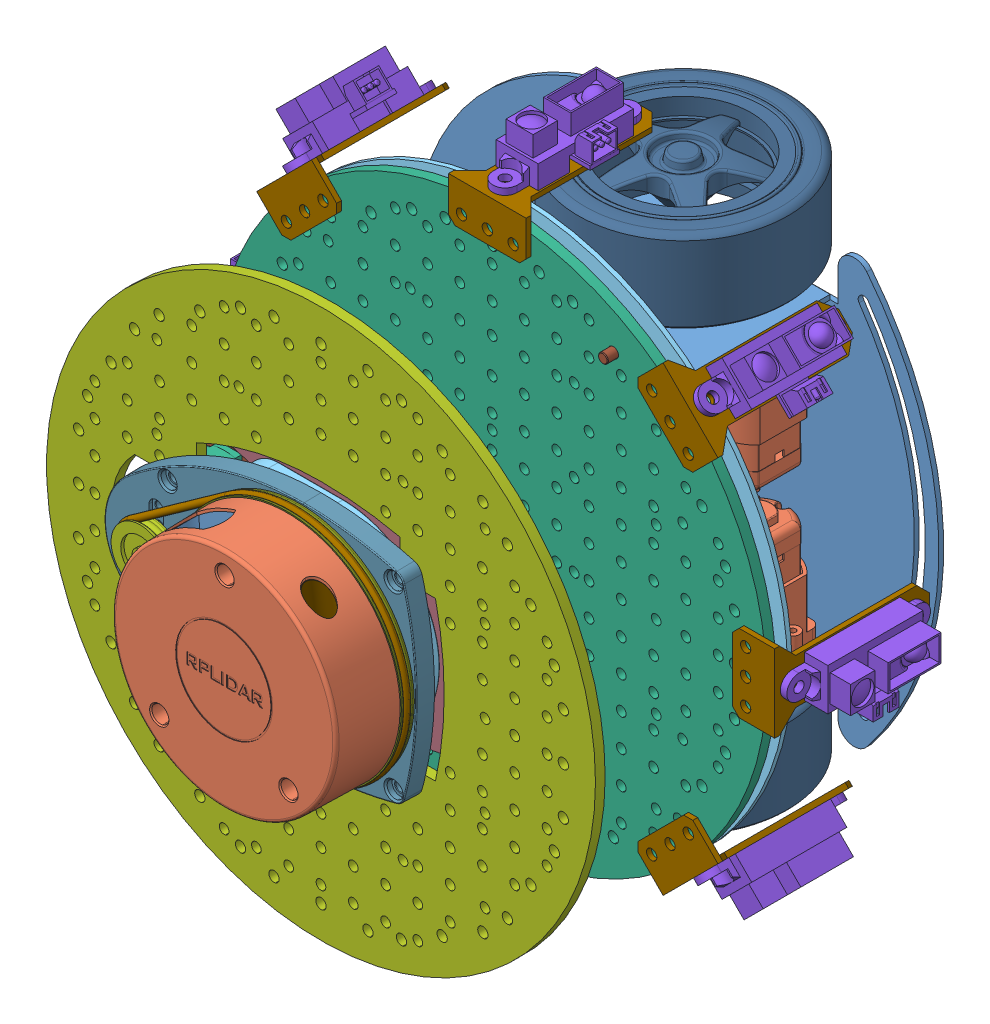
SolidWorks assembly ABOT_2, configuration По умолчанию. Lengths in mm.
Overall size (205 205 173.81).
51 component instances, 33 part files, 41 mates.
Components (placement in the parent):
- LOWER_PLATE-1: LOWER_PLATE [По умолчанию] x (0 1 0) z (1 0 0) size (144.85 55.5 162.2)
- TT_ANGLE_MOTOR_PART-1: TT_ANGLE_MOTOR_PART [По умолчанию] at (11.0834 -43.5 12.4406) x (-1 0 0) z (0 1 0) size (47.1 23 58.3)
- TT_ANGLE_MOTOR_PART-2: TT_ANGLE_MOTOR_PART [По умолчанию] at (11.0834 43.5 16.5594) x (-1 0 0) z (0 -1 0) size (47.1 23 58.3)
- CASTER_WHEEL_CASE-1: CASTER_WHEEL_CASE [Default] at (-78 0 -11) x (0 1 0) z (1 0 0) size (48.4 16.5 32.2)
- CASTER_WHEEL_BALL-1: CASTER_WHEEL_BALL [Default] at (-78 0 -11) x (0 1 0) z (1 0 0) size (14 14 14)
- UPPER_PLATE-1: UPPER_PLATE [Default] at (-10 0 55.5) x (-1 0 0) z (0 0 1) size (169.5 169.5 1.4)
- CUT_PLEX_PLATE_0-1: CUT_PLEX_PLATE_0 [Default] at (-10 0 60.65) x (-1 0 0) z (0 0 1) size (170 170 3)
- CUT_PLEX_PLATE_1-1: CUT_PLEX_PLATE_1 [По умолчанию] at (-10 0 113.65) x (-1 0 0) z (0 0 1) size (170 170 3)
- GP2Y0A41SK0F_AXIS_FRAME-1: GP2Y0A41SK0F_AXIS_FRAME [По умолчанию] at (92.5 0 41.15) x (0 0 -1) z (0 -1 0) size (44.5 13.5 18.9)
- PRINT_SHARP_IR_MOUNTING_BRACKET_VERTICAL-1: PRINT_SHARP_IR_MOUNTING_BRACKET_VERTICAL [Default] at (79 0 65.15) x (-1 0 0) z (0 -1 0) size (13 48 24)
- WHEEL_D65_W26-1: WHEEL_D65_W26 [Predeterminado] at (0 68 14.5) x (0 1 0) z (-0.04348 0 0.999054) size (29 65 65)
- WHEEL_D65_W26-2: WHEEL_D65_W26 [Predeterminado] at (0 -68 14.5) x (0 -1 0) z (-0.342045 0 0.939684) size (29 65 65)
- M3_12H-1: M3_12H [По умолчанию] at (27.525 64.9952 52.9) x (0 0 1) z (-1 0 0) size (14 5.5 5.5)
- M3_NUT-1: M3_NUT [По умолчанию] at (27.525 64.9952 57.5) x (0.986628 0.162989 0) z (0 0 1) size (5.5 6.35 2.4)
- M3_WASHER_NORMAL-1: M3_WASHER_NORMAL [Default] at (27.525 64.9952 55.5) x (-1 0 0) z (0 0 -1) size (6.75 6.75 0.6)
- M3_WASHER_NORMAL-2: M3_WASHER_NORMAL [Default] at (27.525 64.9952 56.9) x (0.997695 0.06786 0) z (0 0 1) size (6.75 6.75 0.6)
- GP2Y0A41SK0F_AXIS_FRAME-13: GP2Y0A41SK0F_AXIS_FRAME [По умолчанию] at (62.4784 -72.4784 41.15) x (0 0 -1) z (-0.707107 -0.707107 0) size (44.5 13.5 18.9)
- GP2Y0A41SK0F_AXIS_FRAME-14: GP2Y0A41SK0F_AXIS_FRAME [По умолчанию] at (-10 -102.5 41.15) x (0 0 -1) z (-1 0 0) size (44.5 13.5 18.9)
- GP2Y0A41SK0F_AXIS_FRAME-15: GP2Y0A41SK0F_AXIS_FRAME [По умолчанию] at (-82.4784 -72.4784 41.15) x (0 0 -1) z (-0.707107 0.707107 0) size (44.5 13.5 18.9)
- GP2Y0A41SK0F_AXIS_FRAME-16: GP2Y0A41SK0F_AXIS_FRAME [По умолчанию] at (-112.5 0 41.15) x (0 0 -1) z (0 1 0) size (44.5 13.5 18.9)
- GP2Y0A41SK0F_AXIS_FRAME-17: GP2Y0A41SK0F_AXIS_FRAME [По умолчанию] at (-82.4784 72.4784 41.15) x (0 0 -1) z (0.707107 0.707107 0) size (44.5 13.5 18.9)
- GP2Y0A41SK0F_AXIS_FRAME-18: GP2Y0A41SK0F_AXIS_FRAME [По умолчанию] at (-10 102.5 41.15) x (0 0 -1) z (1 0 0) size (44.5 13.5 18.9)
- GP2Y0A41SK0F_AXIS_FRAME-19: GP2Y0A41SK0F_AXIS_FRAME [По умолчанию] at (62.4784 72.4784 41.15) x (0 0 -1) z (0.707107 -0.707107 0) size (44.5 13.5 18.9)
- PRINT_SHARP_IR_MOUNTING_BRACKET_VERTICAL-9: PRINT_SHARP_IR_MOUNTING_BRACKET_VERTICAL [Default] at (52.9325 -62.9325 65.15) x (-0.707107 0.707107 0) z (-0.707107 -0.707107 0) size (13 48 24)
- PRINT_SHARP_IR_MOUNTING_BRACKET_VERTICAL-10: PRINT_SHARP_IR_MOUNTING_BRACKET_VERTICAL [Default] at (-10 -89 65.15) x (0 1 0) z (-1 0 0) size (13 48 24)
- PRINT_SHARP_IR_MOUNTING_BRACKET_VERTICAL-11: PRINT_SHARP_IR_MOUNTING_BRACKET_VERTICAL [Default] at (-72.9325 -62.9325 65.15) x (0.707107 0.707107 0) z (-0.707107 0.707107 0) size (13 48 24)
- PRINT_SHARP_IR_MOUNTING_BRACKET_VERTICAL-12: PRINT_SHARP_IR_MOUNTING_BRACKET_VERTICAL [Default] at (-99 0 65.15) x (1 0 0) z (0 1 0) size (13 48 24)
- PRINT_SHARP_IR_MOUNTING_BRACKET_VERTICAL-13: PRINT_SHARP_IR_MOUNTING_BRACKET_VERTICAL [Default] at (-72.9325 62.9325 65.15) x (0.707107 -0.707107 0) z (0.707107 0.707107 0) size (13 48 24)
- PRINT_SHARP_IR_MOUNTING_BRACKET_VERTICAL-14: PRINT_SHARP_IR_MOUNTING_BRACKET_VERTICAL [Default] at (-10 89 65.15) x (0 -1 0) z (1 0 0) size (13 48 24)
- PRINT_SHARP_IR_MOUNTING_BRACKET_VERTICAL-15: PRINT_SHARP_IR_MOUNTING_BRACKET_VERTICAL [Default] at (52.9325 62.9325 65.15) x (-0.707107 -0.707107 0) z (0.707107 -0.707107 0) size (13 48 24)
- LIDAR-1: LIDAR [По умолчанию] at (-79.4738 13.0661 98.954) x (-1 0 0) z (0 1 0) size (102.81 54.41 71.78)
  - 1-1: 1 [По умолчанию] at (-69.4738 21.696 -13.0661) size (96.74 12.71 70.28)
  - 2-1: 2 [По умолчанию] at (-69.4738 23.696 -13.0661) x (1 0 0) z (0 -1 0) size (47 47 7.01)
  - 3-1: 3 [По умолчанию] at (-69.4738 25.696 -13.0661) x (0.00451 0 -0.99999) z (0.99999 0 0.00451) size (70.79 21.41 70.79)
  - 4-1: 4 [По умолчанию] at (-94.6291 38.696 -19.9402) x (0.990886 0 -0.134705) z (0.134705 0 0.990886) size (6.5 6.5 21.2)
  - 5-1: 5 [По умолчанию] at (-69.4738 29.696 -13.0661) x (-0.99999 0 -0.00451) z (0.00451 0 -0.99999) size (15.26 18.52 21.56)
  - 6-1: 6 [По умолчанию] at (-69.4738 29.696 -13.0661) x (-0.99999 0 -0.00451) z (0.00451 0 -0.99999) size (22.09 18.86 24.76)
  - 7-1: 7 [По умолчанию] at (-69.4738 47.696 -13.0661) x (0.99999 0 0.00451) z (0.00451 0 -0.99999) size (70 19.51 70)
  - 8-1: 8 [По умолчанию] at (-69.4738 12.696 -13.0661) x (0.987093 0 -0.160146) z (0.160146 0 0.987093) size (25 1.2 25)
  - 9-1: 9 [По умолчанию] at (-69.4738 11.696 -13.0661) size (55.5 1 57)
  - 10-1: 10 [По умолчанию] at (-69.4738 10.696 -13.0661) size (59.96 11.11 60.96)
  - 11-1: 11 [По умолчанию] at (-23.9738 2.196 -13.0661) x (0 0 -1) z (1 0 0) size (32 30.21 32.01)
  - 12-1: 12 [По умолчанию] at (-23.9738 24.196 -13.0661) x (0.135455 0 -0.990784) z (0.990784 0 0.135455) size (18 5.5 18)
  - 13-1: 13 [По умолчанию] at (-52.5259 38.696 -1.4895) x (0.136926 0.990581 0.000618) z (-0.00451 0 0.99999) size (14 14 11.5)
  - 14-1: 14 [По умолчанию] at (-69.4738 26.196 -13.0661) x (1 0 0) z (0 -1 0) size (90.89 71.78 2)
  - 15-1: 15 [По умолчанию] at (-45.3638 9.296 -13.0661) x (0 0 -1) z (0 -1 0) size (10.15 4.2 4.7)
  - 16-1: 16 [По умолчанию] at (-23.9738 -1.404 -13.0661) x (-0.441218 0 -0.8974) z (0.8974 0 -0.441218) size (32 1.6 32)
  - 17-1: 17 [По умолчанию] at (-36.9138 -3.104 -13.0661) x (0 0 1) z (0 -1 0) size (8.9 5.2 3.4)
  - 19-1: 19 [По умолчанию] at (-69.4738 0.896 -13.0661) x (1 0 0) z (0 0 -1) size (80.7 4.7 70)
  - 20-1: 20 [По умолчанию] at (-69.4738 -0.704 14.0339) x (0 -1 0) z (1 0 0) size (8.2 5 20)
  - 22-1: 22 [По умолчанию] at (-51.7938 -0.804 -13.0661) x (0 0 1) z (1 0 0) size (8.8 4.7 4.36)
Mates (geometry in assembly coordinates):
- Концентричный1: concentric aligned: cylinder of LOWER_PLATE-1 through (0 54 14.5) axis (0 -1 0) radius 4; cylinder of TT_ANGLE_MOTOR_PART-2 through (0 59.3 14.5) axis (0 -1 0) radius 2.7
- Параллельность1: parallel anti-aligned: plane of LOWER_PLATE-1 through (0 0 1.5) normal (0 0 1); plane of TT_ANGLE_MOTOR_PART-2 through (28.5 50.5 3) normal (0 0 -1)
- Совпадение2: coincident anti-aligned: plane of LOWER_PLATE-1 through (-32.5 50.5 55) normal (0 -1 0); plane of TT_ANGLE_MOTOR_PART-2 through (-8.5 50.5 5.5) normal (0 1 0)
- Концентричный2: concentric anti-aligned: cylinder of LOWER_PLATE-1 through (0 54 14.5) axis (0 -1 0) radius 4; cylinder of TT_ANGLE_MOTOR_PART-1 through (0 -59.3 14.5) axis (0 1 0) radius 2.7
- Параллельность2: parallel aligned: plane of LOWER_PLATE-1 through (0 0 1.5) normal (0 0 1); plane of TT_ANGLE_MOTOR_PART-1 through (28.5 -50.5 26) normal (0 0 1)
- Совпадение4: coincident anti-aligned: plane of LOWER_PLATE-1 through (-32.5 -50.5 55) normal (0 1 0); plane of TT_ANGLE_MOTOR_PART-1 through (-8.5 -50.5 23.5) normal (0 -1 0)
- Концентричный17: concentric anti-aligned: cylinder of LOWER_PLATE-1 through (-78 0 1.5) axis (0 0 -1) radius 16; cylinder of CASTER_WHEEL_CASE-1 through (-78 0 -14) axis (0 0 1) radius 16.1
- Концентричный18: concentric aligned: cylinder of LOWER_PLATE-1 through (-78 20 0) axis (0 0 1) radius 2.05; cylinder of CASTER_WHEEL_CASE-1 through (-78 20 -14) axis (0 0 1) radius 2
- Совпадение15: coincident anti-aligned: plane of LOWER_PLATE-1 through (0 0 1.5) normal (0 0 1); plane of CASTER_WHEEL_CASE-1 through (-78 0 1.5) normal (0 0 -1)
- Совпадение16: coordinate: point of CASTER_WHEEL_CASE-1; point of CASTER_WHEEL_BALL-1
- Концентричный22: concentric aligned: cylinder of LOWER_PLATE-1 through (25 -45 55.5) axis (0 0 -1) radius 1.5; cylinder of UPPER_PLATE-1 through (25 -45 56.9) axis (0 0 -1) radius 2
- Концентричный23: concentric aligned: cylinder of LOWER_PLATE-1 through (-25 45 55.5) axis (0 0 -1) radius 1.5; cylinder of UPPER_PLATE-1 through (-25 45 56.9) axis (0 0 -1) radius 2
- Концентричный26: concentric aligned: cylinder of UPPER_PLATE-1 through (-10 0 56.9) axis (0 0 -1) radius 84.75; cylinder of CUT_PLEX_PLATE_0-1 through (-10 0 63.65) axis (0 0 -1) radius 85
- Расстояние2: distance = 3.75 mm anti-aligned: plane of CUT_PLEX_PLATE_0-1 through (-10 0 60.65) normal (0 0 -1); plane of UPPER_PLATE-1 through (-10 0 56.9) normal (0 0 1)
- Концентричный37: concentric anti-aligned: cylinder of GP2Y0A41SK0F_AXIS_FRAME-1 through (84 0 59.65) axis (-1 0 0) radius 1.6; cylinder of PRINT_SHARP_IR_MOUNTING_BRACKET_VERTICAL-1 through (66 0 59.65) axis (1 0 0) radius 1.5
- Концентричный38: concentric anti-aligned: cylinder of GP2Y0A41SK0F_AXIS_FRAME-1 through (84 0 22.65) axis (-1 0 0) radius 1.6; cylinder of PRINT_SHARP_IR_MOUNTING_BRACKET_VERTICAL-1 through (66 0 22.65) axis (1 0 0) radius 1.5
- Совпадение27: coincident anti-aligned: plane of GP2Y0A41SK0F_AXIS_FRAME-1 through (79 0 41.15) normal (-1 0 0); plane of PRINT_SHARP_IR_MOUNTING_BRACKET_VERTICAL-1 through (79 -12 65.15) normal (1 0 0)
- Совпадение28: coincident anti-aligned: plane of PRINT_SHARP_IR_MOUNTING_BRACKET_VERTICAL-1 through (66 -12 63.65) normal (0 0 -1); plane of CUT_PLEX_PLATE_0-1 through (-10 0 63.65) normal (0 0 1)
- Совпадение30: coincident anti-aligned: plane of LOWER_PLATE-1 through (0 0 55.5) normal (0 0 1); plane of UPPER_PLATE-1 through (-10 0 55.5) normal (0 0 -1)
- Совпадение31: coincident anti-aligned: plane of GP2Y0A41SK0F_AXIS_FRAME-1; plane of assembly through (0 0 0) normal (0 1 0)
- Концентричный41: concentric anti-aligned: cylinder of TT_ANGLE_MOTOR_PART-2 through (0 59.3 14.5) axis (0 -1 0) radius 2.7; cylinder of WHEEL_D65_W26-1 through (0 68.8553 14.5) axis (0 1 0) radius 4
- Совпадение35: coincident anti-aligned: plane of LOWER_PLATE-1 through (0 52 55) normal (0 1 0); plane of WHEEL_D65_W26-1 through (0 52 14.5) normal (0 -1 0)
- Концентричный42: concentric anti-aligned: cylinder of TT_ANGLE_MOTOR_PART-1 through (0 -59.3 14.5) axis (0 1 0) radius 2.7; cylinder of WHEEL_D65_W26-2 through (0 -68.8553 14.5) axis (0 -1 0) radius 4
- Совпадение36: coincident anti-aligned: plane of LOWER_PLATE-1 through (0 -52 55) normal (0 -1 0); plane of WHEEL_D65_W26-2 through (0 -52 14.5) normal (0 1 0)
- Концентричный44: concentric anti-aligned: cylinder of M3_12H-1 through (27.525 64.9952 52.9) axis (0 0 -1) radius 1.5; circle of UPPER_PLATE-1
- Концентричный43: concentric anti-aligned: cylinder of M3_12H-1 through (27.525 64.9952 52.9) axis (0 0 -1) radius 1.5; cylinder of M3_WASHER_NORMAL-1 through (27.525 64.9952 54.9) axis (0 0 1) radius 1.55
- Совпадение37: coincident anti-aligned: plane of M3_12H-1 through (27.525 64.9952 54.9) normal (0 0 1); plane of M3_WASHER_NORMAL-1 through (27.525 64.9952 54.9) normal (0 0 -1)
- Совпадение38: coincident anti-aligned: plane of UPPER_PLATE-1 through (-10 0 55.5) normal (0 0 -1); plane of M3_WASHER_NORMAL-1 through (27.525 64.9952 55.5) normal (0 0 1)
- Концентричный45: concentric aligned: cylinder of M3_12H-1 through (27.525 64.9952 52.9) axis (0 0 -1) radius 1.5; cylinder of M3_WASHER_NORMAL-2 through (27.525 64.9952 57.5) axis (0 0 -1) radius 1.55
- Концентричный46: concentric aligned: cylinder of M3_12H-1 through (27.525 64.9952 52.9) axis (0 0 -1) radius 1.5; cylinder of M3_NUT-1 through (27.525 64.9952 59.9) axis (0 0 -1) radius 1.5
- Совпадение39: coincident anti-aligned: plane of M3_NUT-1 through (27.525 64.9952 57.5) normal (0 0 -1); plane of M3_WASHER_NORMAL-2 through (27.525 64.9952 57.5) normal (0 0 1)
- Совпадение40: coincident anti-aligned: plane of UPPER_PLATE-1 through (-10 0 56.9) normal (0 0 1); plane of M3_WASHER_NORMAL-2 through (27.525 64.9952 56.9) normal (0 0 -1)
- Концентричный47: concentric aligned: cylinder of CUT_PLEX_PLATE_0-1 through (70 -8 63.65) axis (0 0 -1) radius 1.6; cylinder of PRINT_SHARP_IR_MOUNTING_BRACKET_VERTICAL-1 through (70 -8 108.85) axis (0 0 -1) radius 1.6
- Концентричный49: concentric aligned: cylinder of CUT_PLEX_PLATE_0-1 through (70 8 63.65) axis (0 0 -1) radius 1.6; cylinder of PRINT_SHARP_IR_MOUNTING_BRACKET_VERTICAL-1 through (70 8 108.85) axis (0 0 -1) radius 1.6
- Концентричный51: concentric aligned: cylinder of CUT_PLEX_PLATE_0-1 through (-10 0 63.65) axis (0 0 -1) radius 85; cylinder of CUT_PLEX_PLATE_1-1 through (-10 0 116.65) axis (0 0 -1) radius 85
- Концентричный53: concentric aligned: cylinder of CUT_PLEX_PLATE_1-1 through (18 -28 116.65) axis (0 0 -1) radius 1.5; cylinder of LIDAR-1/1-1 through (18 -28 119.95) axis (0 0 -1) radius 1.5
- Концентричный54: concentric aligned: cylinder of CUT_PLEX_PLATE_0-1 through (27.525 64.9952 63.65) axis (0 0 -1) radius 1.6; cylinder of M3_12H-1 through (27.525 64.9952 52.9) axis (0 0 -1) radius 1.5
- Совпадение41: coincident anti-aligned: plane of CUT_PLEX_PLATE_1-1 through (-10 0 116.65) normal (0 0 1); plane of LIDAR-1/1-1 through (-10 62.2833 116.65) normal (0 0 -1)
- Расстояние3: distance = 50 mm anti-aligned: plane of CUT_PLEX_PLATE_0-1 through (-10 0 63.65) normal (0 0 1); plane of CUT_PLEX_PLATE_1-1 through (-10 0 113.65) normal (0 0 -1)
- Концентричный57: concentric aligned: cylinder of CUT_PLEX_PLATE_1-1 through (-52 20 116.65) axis (0 0 -1) radius 1.5; cylinder of LIDAR-1/1-1 through (-52 20 119.95) axis (0 0 -1) radius 1.5
- Концентричный58: concentric aligned: cylinder of CUT_PLEX_PLATE_0-1 through (65.05 14.55 63.65) axis (0 0 -1) radius 1.6; cylinder of CUT_PLEX_PLATE_1-1 through (65.05 14.55 116.65) axis (0 0 -1) radius 1.6
